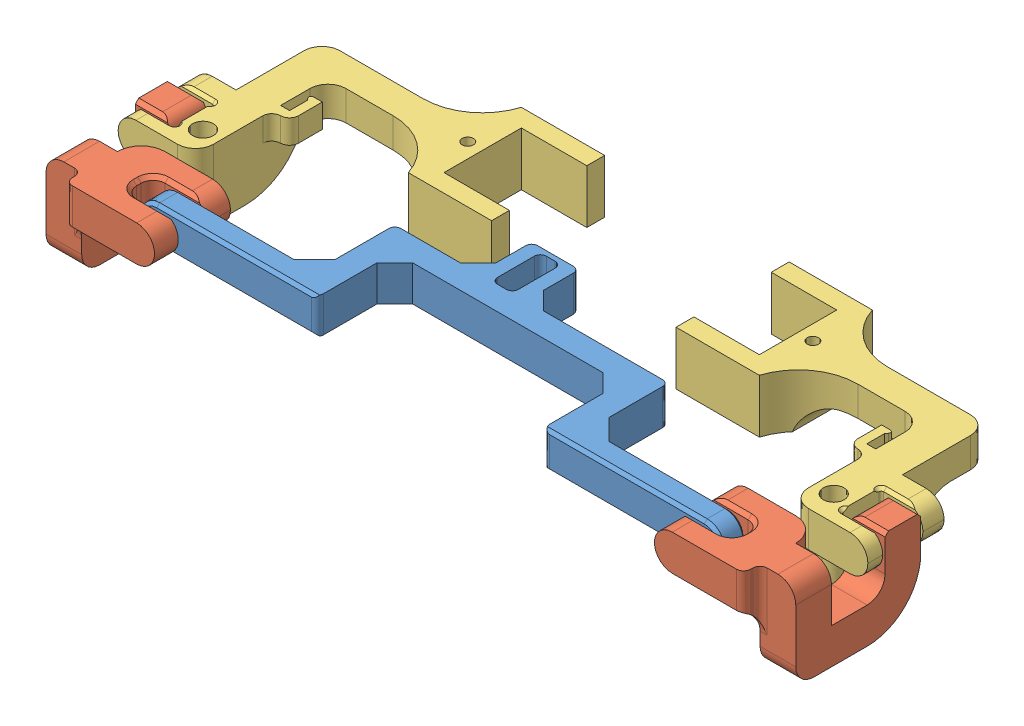
SolidWorks assembly 15+11+16 (Direccion), configuration Predeterminado. Lengths in mm.
Overall size (126 15.06 49.38).
5 component instances, 3 part files, 30 mates.
Components (placement in the parent):
- 15-1: 15 [Predeterminado] at (-56.802 1.6746 98) size (98 6 26)
- 16R-1: 16R [Predeterminado] at (-74.802 4.6746 97.62) x (0 -1 0) z (1 0 0) size (15 24 21)
- 16R-5: 16R [16L] at (51.198 4.6746 97.62) x (0 1 0) z (-1 0 0) size (15 24 21)
- 11R-8: 11R [Predeterminado] at (-61.802 -3.3254 87.24) x (0 1 0) z (-1 0 0) size (11.6 34.26 47.5)
- 11R-12: 11R [11L] at (-30.802 -3.3254 87.24) x (0 1 0) z (-1 0 0) size (11.6 34.26 47.5)
Mates (geometry in assembly coordinates):
- Concéntrica3: concentric: circle of assembly; circle of assembly; circle of 15-1; circle of 16R-1
- Distancia2: distance = 0.38 mm: plane of assembly; plane of assembly; plane of 15-1 through (-56.802 1.6746 98) normal (0 0 -1); plane of 16R-1 through (-68.802 4.6746 97.62) normal (0 0 1)
- Concéntrica4: concentric: circle of 11R-8; circle of 16R-1
- Distancia3: distance = 0.38 mm: plane of 11R-8 through (-74.802 4.6746 82.24) normal (0 0 1); plane of 16R-1 through (-68.802 4.6746 82.62) normal (0 0 -1)
- Concéntrica5: concentric: circle of assembly; circle of assembly; circle of 15-1; circle of 16R-5
- Distancia4: distance = 0.38 mm: plane of assembly; plane of assembly; plane of 16R-5 through (45.198 4.6746 97.62) normal (0 0 1); plane of 15-1 through (-56.802 1.6746 98) normal (0 0 -1)
- Concéntrica6: concentric: circle of ?; circle of 16R-5
- Distancia5: distance = 0.38 mm: plane of ? through (44.3329 -14.9588 89) normal (0 0 -1); plane of 16R-5 through (45.198 4.6746 88.62) normal (0 0 1)
- Paralelo2: parallel: unknown of ?; plane of ? through (38.2389 -3.4064 87.24) normal (-0.999967 -0.008115 0)
- Concéntrica7: concentric: circle of 16R-5; circle of ?
- Distancia6: distance = 0.38 mm: plane of ? through (51.198 4.6746 82.24) normal (0 0 1); plane of 16R-5 through (45.198 4.6746 82.62) normal (0 0 -1)
- Concéntrica9: concentric: unknown of ?; unknown of ?
- Concéntrica11: concentric: circle of ?; circle of ?
- Concéntrica12: concentric: circle of ?; circle of ?
- Concéntrica13: concentric: circle of ?; circle of ?
- Concéntrica15: concentric: circle of 16R-5; circle of ?
- Distancia8: distance = 0.38 mm: plane of ? through (51.0026 4.8581 82.24) normal (0 0 1); plane of 16R-5 through (45.198 4.6746 82.62) normal (0 0 -1)
- Concéntrica16: concentric: circle of assembly; circle of assembly; circle of 16R-1; circle of 11R-8
- Distancia9: distance = 0.38 mm: plane of assembly; plane of assembly; plane of 16R-1 through (-68.802 4.6746 88.62) normal (0 0 1); plane of 11R-8 through (-67.802 -14.7883 89) normal (0 0 -1)
- Concéntrica17: concentric: circle of 16R-5; circle of ?
- Distancia10: distance = 0.38 mm: plane of ? through (51.198 4.6746 82.24) normal (0 0 1); plane of 16R-5 through (45.198 4.6746 82.62) normal (0 0 -1)
- Coincidente27: coincident: plane of 15-1 through (-56.802 4.6746 102) normal (0 1 0); plane of ? through (44.198 4.6746 78.9259) normal (0 1 0)
- Concéntrica18: concentric: circle of 16R-5; circle of ?
- Distancia11: distance = 0.38 mm: plane of ? through (51.198 4.6746 82.24) normal (0 0 1); plane of 16R-5 through (45.198 4.6746 82.62) normal (0 0 -1)
- Concéntrica19: concentric: circle of assembly; circle of assembly; circle of 16R-5; circle of 11R-12
- Distancia12: distance = 0.38 mm: plane of assembly; plane of assembly; plane of 11R-12 through (44.198 -14.7883 89) normal (0 0 -1); plane of 16R-5 through (45.198 4.6746 88.62) normal (0 0 1)
- Paralelo3: parallel: unknown of ?; unknown of ?
- Perpendicular1: perpendicular: plane of 15-1 through (-56.802 4.6746 102) normal (0 1 0); unknown of ?
- Coincidente28: coincident: plane of 15-1 through (-56.802 4.6746 102) normal (0 1 0); plane of 16R-5 through (30.198 4.6746 93.62) normal (0 1 0)
- Coincidente29: coincident: plane of 15-1 through (-56.802 4.6746 102) normal (0 1 0); plane of 16R-1 through (-53.802 4.6746 93.62) normal (0 1 0)
